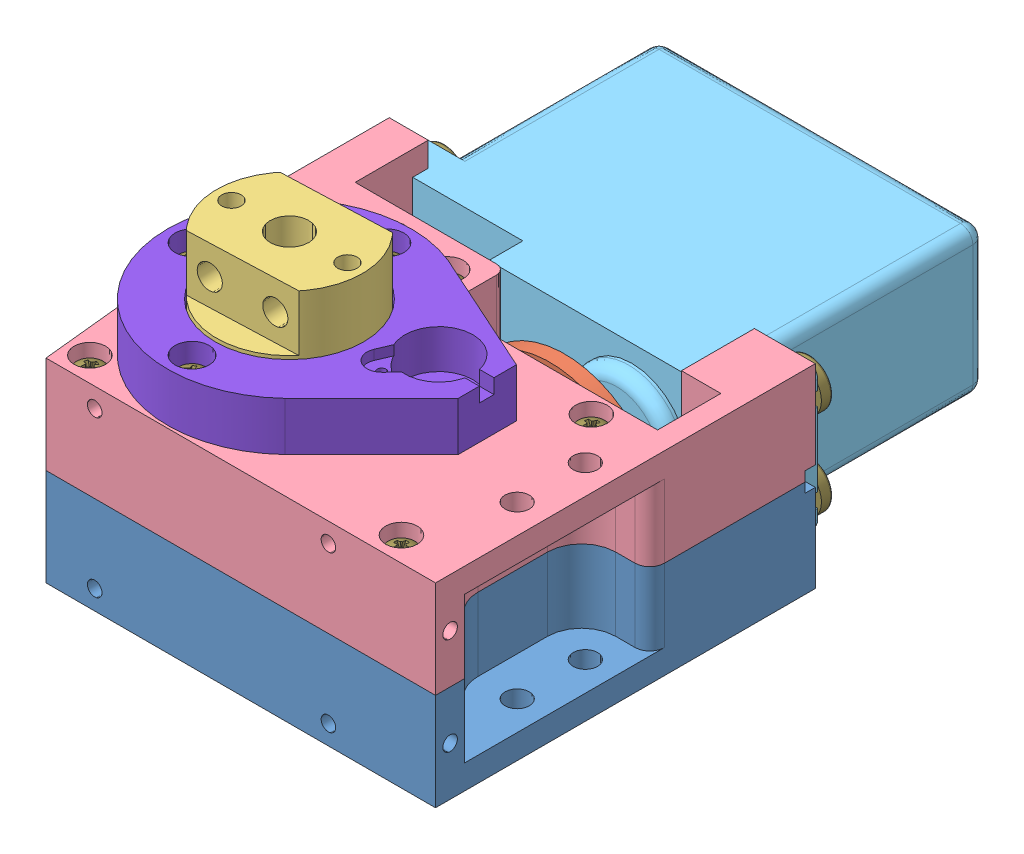
SolidWorks assembly gearbox, configuration Default. Lengths in mm.
Overall size (88.25 74 125.51).
28 component instances, 12 part files, 61 mates.
Components (placement in the parent):
- bottom housing-1: bottom housing [Default] at (7.4002 -24.2748 89.7718) x (1 0 0) z (0 1 0) size (87.5 78 20)
- wormscrew-1: wormscrew [Default] at (21.4002 -4.2748 74.7718) x (-0.98645 0.164063 0) z (0 0 1) size (40 40 51)
- driveshaft cog-1: driveshaft cog [Default] at (-6.5998 -9.2748 103.2718) x (-0.999334 0 0.036493) z (0 1 0) size (49.29 49.31 47)
- top housing-1: top housing [Default] at (-6.5998 15.7252 103.2718) x (-1 0 0) z (0 -1 0) size (87.5 78 40)
- HS-805BB-1: HS-805BB [Default] at (2.9002 10.7252 28.6693) x (1 0 0) z (0 -1 0) size (83 68.8 30)
- 608ZZ-4: 608ZZ [Default] at (21.4002 -4.2748 120.5718) x (0.996867 0.079098 0) z (0 0 1) size (22 22 7)
- 6806 30x42x7-1: 6806 30x42x7 [Default] at (-6.5998 -15.2748 103.2718) x (0.979879 0 0.199591) z (0 -1 0) size (42 42 7)
- 6806 30x42x7-2: 6806 30x42x7 [Default] at (-6.5998 2.7252 103.2718) x (0.968275 0 0.249889) z (0 1 0) size (42 42 7)
- pot holder-1: pot holder [Default] at (-6.5998 15.7252 103.2718) x (0 0 -1) z (0 1 0) size (50 60 10)
- cog brace-1: cog brace [Default] at (18.6002 10.0252 104.6718) x (-1 0 0) z (0 -1 0) size (8.5 22.65 3)
- pot cog-1: pot cog [Default] at (18.6002 10.0252 97.7718) x (0.754384 0 -0.656434) z (0 1 0) size (28 27.88 7.9)
- driveshaft-1: driveshaft [Default] at (-6.5998 -9.2748 103.2718) x (0.999334 0 -0.036493) z (0 -1 0) size (36.44 35.48 27)
- Pan Head Cross Recess Screw_ISO-22: Pan Head Cross Recess Screw_ISO [ISO 7045 - M3 x 10 - Z --- 10N] at (-26.5998 23.1252 103.2718) x (0 -1 0) z (0 0 1) size (12.35 5.6 5.6)
- Pan Head Cross Recess Screw_ISO-23: Pan Head Cross Recess Screw_ISO [ISO 7045 - M3 x 10 - Z --- 10N] at (-6.5998 23.1252 123.2718) x (0 -1 0) z (0.495758 0 0.868461) size (12.35 5.6 5.6)
- Pan Head Cross Recess Screw_ISO-24: Pan Head Cross Recess Screw_ISO [ISO 7045 - M3 x 10 - Z --- 10N] at (-6.5998 23.1252 83.2718) x (0 -1 0) z (0.927545 0 0.373711) size (12.35 5.6 5.6)
- Pan Head Cross Recess Screw_ISO-3: Pan Head Cross Recess Screw_ISO [ISO 7045 - M5 x 12 - Z --- 12N] at (-34.5998 -13.2748 42.0718) x (0 0 1) z (-1 0 0) size (15.63 9.5 9.5)
- Pan Head Cross Recess Screw_ISO-4: Pan Head Cross Recess Screw_ISO [ISO 7045 - M5 x 12 - Z --- 12N] at (-34.5998 4.7252 42.0718) x (0 0 1) z (-1 0 0) size (15.63 9.5 9.5)
- Pan Head Cross Recess Screw_ISO-9: Pan Head Cross Recess Screw_ISO [ISO 7045 - M3 x 30 - Z --- 25N] at (36.9002 14.1252 123.7718) x (0 -1 0) z (0 0 1) size (32.35 5.6 5.6)
- Pan Head Cross Recess Screw_ISO-13: Pan Head Cross Recess Screw_ISO [ISO 7045 - M3 x 30 - Z --- 25N] at (-18.0998 -22.6748 69.7718) x (0 1 0) z (0 0 1) size (32.35 5.6 5.6)
- Pan Head Cross Recess Screw_ISO-14: Pan Head Cross Recess Screw_ISO [ISO 7045 - M3 x 30 - Z --- 25N] at (34.9002 14.1252 82.7718) x (0 -1 0) z (-0.981395 0 -0.191999) size (32.35 5.6 5.6)
- Pan Head Cross Recess Screw_ISO-15: Pan Head Cross Recess Screw_ISO [ISO 7045 - M3 x 30 - Z --- 25N] at (-5.5998 14.1252 71.7718) x (0 -1 0) z (0.38373 0 0.923445) size (32.35 5.6 5.6)
- Pan Head Cross Recess Screw_ISO-16: Pan Head Cross Recess Screw_ISO [ISO 7045 - M2 x 6 - Z --- 6N] at (18.6002 6.9252 115.2718) x (0 1 0) z (0.879308 0 -0.476254) size (7.57 4 4)
- Pan Head Cross Recess Screw_ISO-18: Pan Head Cross Recess Screw_ISO [ISO 7045 - M3 x 5 - Z --- 5N] at (-5.9795 -13.6748 120.2605) x (0 1 0) z (-0.276322 0 0.961065) size (7.35 5.6 5.6)
- Pan Head Cross Recess Screw_ISO-19: Pan Head Cross Recess Screw_ISO [ISO 7045 - M3 x 5 - Z --- 5N] at (7.8026 -13.6748 94.2402) x (0 1 0) z (0 0 1) size (7.35 5.6 5.6)
- Pan Head Cross Recess Screw_ISO-20: Pan Head Cross Recess Screw_ISO [ISO 7045 - M3 x 5 - Z --- 5N] at (-21.6227 -13.6748 95.3147) x (0 1 0) z (-0.051559 0 0.99867) size (7.35 5.6 5.6)
- Pan Head Cross Recess Screw_ISO-21: Pan Head Cross Recess Screw_ISO [ISO 7045 - M3 x 30 - Z --- 25N] at (-27.0895 14.1252 123.7718) x (0 -1 0) z (-0.304842 0 0.952403) size (32.35 5.6 5.6)
- Pan Head Cross Recess Screw_ISO-2: Pan Head Cross Recess Screw_ISO [ISO 7045 - M5 x 12 - Z --- 12N] at (40.4002 4.7252 42.0718) x (0 0 1) z (0.747712 -0.664023 0) size (15.63 9.5 9.5)
- Pan Head Cross Recess Screw_ISO-1: Pan Head Cross Recess Screw_ISO [ISO 7045 - M5 x 12 - Z --- 12N] at (40.4002 -13.2748 42.0718) x (0 0 1) z (0.337086 -0.941474 0) size (15.63 9.5 9.5)
Mates (geometry in assembly coordinates):
- Coincident9: coincident anti-aligned: plane of bottom housing-1 through (-34.0998 -4.2748 50.7718) normal (0 0 -1); plane of HS-805BB-1 through (-38.5998 -19.2748 50.7718) normal (0 0 1)
- Concentric1: concentric aligned: circle of wormscrew-1; circle of HS-805BB-1
- Coincident30: coincident: circle of bottom housing-1; circle of top housing-1
- Coincident35: coincident anti-aligned: plane of bottom housing-1 through (36.4002 11.2494 65.7718) normal (-1 0 0); plane of HS-805BB-1 through (36.4002 -19.2748 50.7718) normal (1 0 0)
- Concentric9: concentric aligned: circle of bottom housing-1; cylinder of top housing-1
- Concentric10: concentric aligned: circle of bottom housing-1; circle of top housing-1
- Concentric11: concentric aligned: circle of bottom housing-1; circle of HS-805BB-1
- Distance1: distance = 1 mm anti-aligned: plane of bottom housing-1 through (42.4002 -14.2748 78.7718) normal (0 0 -1); plane of wormscrew-1 through (21.4002 -4.2748 77.7718) normal (0 0 1)
- Coincident38: coincident anti-aligned: cylinder of wormscrew-1; circle of 608ZZ-4
- Coincident39: coincident anti-aligned: plane of bottom housing-1 through (32.6502 -15.4748 127.5718) normal (0 0 -1); plane of 608ZZ-4 through (21.4002 -4.2748 127.5718) normal (0 0 1)
- Coincident40: coincident anti-aligned: circle of top housing-1; circle of HS-805BB-1
- Coincident41: coincident anti-aligned: plane of 6806 30x42x7-1 through (-6.5998 -22.2748 103.2718) normal (0 -1 0); plane of bottom housing-1 through (-6.5998 -22.2748 103.2718) normal (0 1 0)
- Concentric12: concentric aligned: cylinder of bottom housing-1; cylinder of 6806 30x42x7-1
- Coincident42: coincident anti-aligned: plane of 6806 30x42x7-2 through (-6.5998 9.7252 103.2718) normal (0 1 0); plane of top housing-1 through (-6.5998 9.7252 103.2718) normal (0 -1 0)
- Concentric13: concentric aligned: cylinder of top housing-1; cylinder of 6806 30x42x7-2
- Coincident43: coincident anti-aligned: plane of driveshaft cog-1 through (-6.5998 2.7252 103.2718) normal (0 1 0); plane of 6806 30x42x7-2 through (-6.5998 2.7252 103.2718) normal (0 -1 0)
- Coincident46: coincident aligned: circle of pot holder-1; circle of top housing-1
- Concentric19: concentric anti-aligned: cylinder of driveshaft cog-1; circle of top housing-1
- Coincident54: coincident anti-aligned: plane of driveshaft-1 through (-6.5998 -9.2748 103.2718) normal (0 1 0); plane of driveshaft cog-1 through (-6.5998 -9.2748 103.2718) normal (0 -1 0)
- Concentric20: concentric aligned: cylinder of 6806 30x42x7-1; cylinder of driveshaft-1
- Concentric25: concentric anti-aligned: cylinder of HS-805BB-1; cylinder of Pan Head Cross Recess Screw_ISO-2
- Coincident57: coincident anti-aligned: plane of HS-805BB-1 through (36.4002 -19.2748 45.7718) normal (0 0 -1); plane of Pan Head Cross Recess Screw_ISO-2 through (38.7401 2.856 45.7718) normal (0 0 1)
- Concentric26: concentric anti-aligned: cylinder of HS-805BB-1; cylinder of Pan Head Cross Recess Screw_ISO-1
- Coincident58: coincident anti-aligned: plane of HS-805BB-1 through (36.4002 -19.2748 45.7718) normal (0 0 -1); plane of Pan Head Cross Recess Screw_ISO-1 through (38.0465 -14.1175 45.7718) normal (0 0 1)
- Concentric27: concentric anti-aligned: cylinder of HS-805BB-1; cylinder of Pan Head Cross Recess Screw_ISO-3
- Coincident59: coincident anti-aligned: plane of HS-805BB-1 through (-30.5998 -19.2748 45.7718) normal (0 0 -1); plane of Pan Head Cross Recess Screw_ISO-3 through (-34.5998 -10.7748 45.7718) normal (0 0 1)
- Concentric28: concentric anti-aligned: cylinder of HS-805BB-1; cylinder of Pan Head Cross Recess Screw_ISO-4
- Coincident60: coincident anti-aligned: plane of HS-805BB-1 through (-30.5998 -19.2748 45.7718) normal (0 0 -1); plane of Pan Head Cross Recess Screw_ISO-4 through (-34.5998 7.2252 45.7718) normal (0 0 1)
- Concentric34: concentric aligned: circle of top housing-1; cylinder of Pan Head Cross Recess Screw_ISO-9
- Coincident66: coincident anti-aligned: plane of top housing-1 through (35.2002 11.7252 123.7718) normal (0 1 0); plane of Pan Head Cross Recess Screw_ISO-9 through (38.4002 11.7252 123.7718) normal (0 -1 0)
- Concentric36: concentric aligned: cylinder of Pan Head Cross Recess Screw_ISO-14; cylinder of top housing-1
- Coincident67: coincident anti-aligned: plane of top housing-1 through (33.2002 11.7252 82.7718) normal (0 1 0); plane of Pan Head Cross Recess Screw_ISO-14 through (34.6122 11.7252 84.2439) normal (0 -1 0)
- Concentric37: concentric aligned: cylinder of Pan Head Cross Recess Screw_ISO-15; cylinder of top housing-1
- Coincident68: coincident anti-aligned: plane of top housing-1 through (-7.2998 11.7252 71.7718) normal (0 1 0); plane of Pan Head Cross Recess Screw_ISO-15 through (-4.2147 11.7252 71.1962) normal (0 -1 0)
- Concentric38: concentric anti-aligned: cylinder of top housing-1; cylinder of Pan Head Cross Recess Screw_ISO-13
- Coincident69: coincident anti-aligned: plane of Pan Head Cross Recess Screw_ISO-13 through (-19.5998 -20.2748 69.7718) normal (0 1 0); plane of bottom housing-1 through (-18.0998 -20.2748 69.7718) normal (0 -1 0)
- Concentric41: concentric aligned: cylinder of top housing-1; cylinder of Pan Head Cross Recess Screw_ISO-16
- Coincident71: coincident anti-aligned: plane of cog brace-1 through (14.1002 8.5252 111.6718) normal (0 -1 0); plane of Pan Head Cross Recess Screw_ISO-16 through (19.0764 8.5252 116.1511) normal (0 1 0)
- Concentric42: concentric aligned: cylinder of driveshaft cog-1; cylinder of Pan Head Cross Recess Screw_ISO-18
- Concentric43: concentric aligned: cylinder of driveshaft-1; cylinder of Pan Head Cross Recess Screw_ISO-18
- Coincident72: coincident anti-aligned: plane of driveshaft-1 through (-5.9795 -11.2748 120.2605) normal (0 -1 0); plane of Pan Head Cross Recess Screw_ISO-18 through (-7.4211 -11.2748 119.846) normal (0 1 0)
- Concentric44: concentric aligned: cylinder of Pan Head Cross Recess Screw_ISO-20; cylinder of driveshaft-1
- Coincident73: coincident anti-aligned: plane of driveshaft-1 through (-21.6227 -11.2748 95.3147) normal (0 -1 0); plane of Pan Head Cross Recess Screw_ISO-20 through (-23.1207 -11.2748 95.2374) normal (0 1 0)
- Coincident74: coincident aligned: circle of driveshaft-1; cylinder of Pan Head Cross Recess Screw_ISO-19
- Coincident75: coincident anti-aligned: plane of driveshaft-1 through (7.8026 -11.2748 94.2402) normal (0 -1 0); plane of Pan Head Cross Recess Screw_ISO-19 through (6.3026 -11.2748 94.2402) normal (0 1 0)
- Concentric45: concentric aligned: circle of top housing-1; cylinder of Pan Head Cross Recess Screw_ISO-21
- Coincident76: coincident anti-aligned: plane of top housing-1 through (-28.7895 11.7252 123.7718) normal (0 1 0); plane of Pan Head Cross Recess Screw_ISO-21 through (-25.6609 11.7252 124.2291) normal (0 -1 0)
- Concentric46: concentric aligned: circle of top housing-1; circle of pot holder-1
- Concentric47: concentric anti-aligned: cylinder of pot holder-1; cylinder of Pan Head Cross Recess Screw_ISO-23
- Coincident78: coincident anti-aligned: plane of pot holder-1 through (-6.5998 20.7252 123.2718) normal (0 1 0); plane of Pan Head Cross Recess Screw_ISO-23 through (-5.2971 20.7252 122.5282) normal (0 -1 0)
- Concentric48: concentric anti-aligned: cylinder of pot holder-1; cylinder of Pan Head Cross Recess Screw_ISO-24
- Coincident79: coincident anti-aligned: plane of pot holder-1 through (-6.5998 20.7252 83.2718) normal (0 1 0); plane of Pan Head Cross Recess Screw_ISO-24 through (-6.0393 20.7252 81.8805) normal (0 -1 0)
- Coincident80: coincident anti-aligned: plane of pot holder-1 through (-26.5998 20.7252 103.2718) normal (0 1 0); plane of Pan Head Cross Recess Screw_ISO-22 through (-25.0998 20.7252 103.2718) normal (0 -1 0)
- Concentric49: concentric anti-aligned: cylinder of pot holder-1; cylinder of Pan Head Cross Recess Screw_ISO-22
- GearMate2: gear = 0.001 : 0.013: circle of driveshaft cog-1; circle of wormscrew-1
- GearMate3: gear = 0.001 : 0.001: circle of pot cog-1; circle of driveshaft cog-1
- Concentric50: concentric aligned: cylinder of cog brace-1; cylinder of Pan Head Cross Recess Screw_ISO-16
- Concentric52: concentric aligned: circle of pot holder-1; cylinder of pot cog-1
- Coincident85: coincident anti-aligned: circle of top housing-1; plane of pot cog-1 through (7.4289 13.9252 95.8274) normal (0 1 0)
- Coincident86: coincident anti-aligned: plane of cog brace-1 through (16.3502 10.0252 97.6718) normal (0 1 0); plane of pot cog-1 through (12.3683 10.0252 96.8971) normal (0 -1 0)
- Concentric53: concentric anti-aligned: unknown of cog brace-1; unknown of pot cog-1
